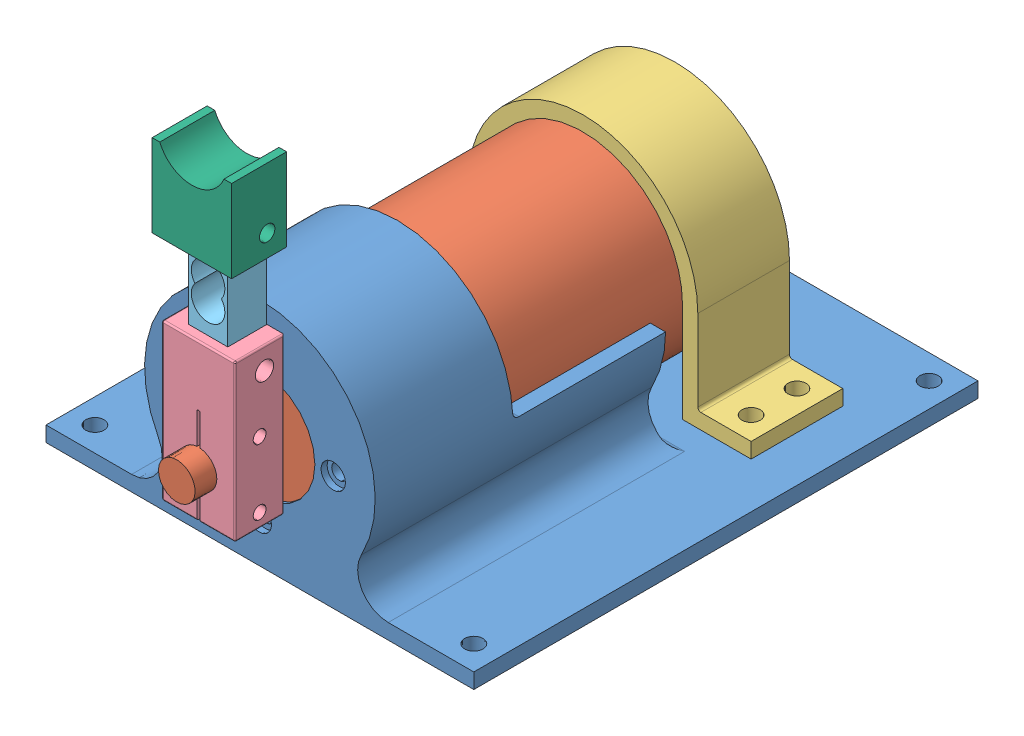
SolidWorks assembly Assemblage_3, configuration Défaut. Lengths in mm.
Overall size (140 127.09 192.2).
8 component instances, 8 part files, 18 mates.
Components (placement in the parent):
- Bati court-1: Bati court [Défaut] at (-75.3045 -22.8426 165) size (140 75.5 165)
- Moteur-1: Moteur [Défaut] at (-5.3045 14.9074 192.2) x (0 0 -1) z (-0.975628 -0.219432 0) size (184.4 65 65)
- Cale moteur-1: Cale moteur [Défaut] at (-5.2545 -17.8426 59.3) x (-1 0 0) z (0 0 -1) size (110 70.1 30)
- Pièce serrage poignée-moteur-1: Pièce serrage poignée-moteur [Défaut] at (-17.3045 -0.0926 169.1) size (24 51 16)
- Capteur force-1: Capteur force [Défaut] at (-11.7045 91.1574 169.2) x (0 -1 0) z (0 0 1) size (55.25 12.7 12.7)
- Embout_court-1: Embout_court [Défaut] at (7.6355 76.1574 187.2) x (-1 0 0) z (0 0 -1) size (26 27 18)
- Entretoise Moteur-Encodeur-1: Entretoise Moteur-Encodeur [Défaut] at (-5.3045 14.9074 28.6) x (-0.923728 -0.383049 0) z (0 0 -1) size (41 41 4.5)
- Encoder-1: Encoder [Défaut] at (-5.3045 14.9074 24.1) x (-1 0 0) z (0 0 -1) size (28.58 37.39 10.34)
Mates (geometry in assembly coordinates):
- Coaxiale1: concentric aligned: cylinder of Bati court-1 through (-5.3045 14.9074 70) axis (0 0 1) radius 32.75; cylinder of Moteur-1 through (-5.3045 14.9074 192.2) axis (0 0 1) radius 32.5
- Coïncidente1: coincident anti-aligned: plane of Bati court-1 through (-75.3045 -17.8426 160) normal (0 0 -1); plane of Moteur-1 through (-1.3547 -2.6539 160) normal (0 0 1)
- Coïncidente2: coincident anti-aligned: plane of Bati court-1 through (-75.3045 -17.8426 165) normal (0 1 0); plane of Cale moteur-1 through (49.7455 -17.8426 29.3) normal (0 -1 0)
- Coïncidente3: coincident anti-aligned: plane of Moteur-1 through (1.7173 -16.3127 34.3) normal (0 0 -1); plane of Cale moteur-1 through (-5.2545 14.7074 34.3) normal (0 0 1)
- Tangent3: tangent anti-aligned: cylinder of Moteur-1 through (-5.3045 14.9074 192.2) axis (0 0 1) radius 32.5; plane of Cale moteur-1 through (-37.8045 14.7074 -62.7653) normal (1 0 0)
- Coaxiale6: concentric anti-aligned: cylinder of Moteur-1 through (-5.3045 14.9074 192.2) axis (0 0 1) radius 6; cylinder of Pièce serrage poignée-moteur-1 through (-5.3045 14.9074 185.1) axis (0 0 -1) radius 6
- Distance1: distance = 5 mm anti-aligned: plane of Pièce serrage poignée-moteur-1 through (-17.3045 -0.0926 169.1) normal (0 0 -1); plane of Moteur-1 through (-3.9879 9.0536 164.1) normal (0 0 1)
- Coïncidente5: coincident anti-aligned: plane of Pièce serrage poignée-moteur-1 through (-17.3045 35.9074 169.1) normal (0 1 0); plane of Capteur force-1 through (-11.7045 35.9074 181.9) normal (0 -1 0)
- Coïncidente6: coincident anti-aligned: plane of Pièce serrage poignée-moteur-1 through (-11.7045 35.9074 169.1) normal (1 0 0); plane of Capteur force-1 through (-11.7045 91.1574 181.9) normal (-1 0 0)
- Coïncidente7: coincident anti-aligned: plane of Pièce serrage poignée-moteur-1 through (-11.7045 35.9074 181.9) normal (0 0 -1); plane of Capteur force-1 through (-5.3545 66.898 181.9) normal (0 0 1)
- Coïncidente8: coincident anti-aligned: plane of Capteur force-1 through (0.9955 91.1574 181.9) normal (1 0 0); plane of Embout_court-1 through (0.9955 91.1574 181.9) normal (-1 0 0)
- Coïncidente9: coincident anti-aligned: plane of Capteur force-1 through (-5.3545 66.898 181.9) normal (0 0 1); plane of Embout_court-1 through (7.6355 76.1574 181.9) normal (0 0 -1)
- Coïncidente10: coincident anti-aligned: plane of Capteur force-1 through (-11.7045 91.1574 181.9) normal (0 1 0); plane of Embout_court-1 through (0.9955 91.1574 181.9) normal (0 -1 0)
- Coïncidente11: coincident anti-aligned: plane of Moteur-1 through (-0.6964 -5.5808 28.6) normal (0 0 -1); plane of Entretoise Moteur-Encodeur-1 through (-5.3045 14.9074 28.6) normal (0 0 1)
- Coaxiale7: concentric anti-aligned: circle of Moteur-1; circle of Entretoise Moteur-Encodeur-1
- Coïncidente13: coincident anti-aligned: plane of Entretoise Moteur-Encodeur-1 through (-5.3045 14.9074 24.1) normal (0 0 -1); plane of Encoder-1 through (-5.3045 14.9074 24.1) normal (0 0 1)
- Coaxiale8: concentric aligned: cylinder of Moteur-1 through (-5.3045 14.9074 192.2) axis (0 0 1) radius 4; cylinder of Encoder-1 through (-5.3045 14.9074 16.76) axis (0 0 1) radius 4
- Parallèle1: parallel aligned: plane of Cale moteur-1 through (-42.8045 -12.8426 29.3) normal (-1 0 0); plane of Encoder-1 through (-19.5945 1.2163 16.76) normal (-1 0 0)
